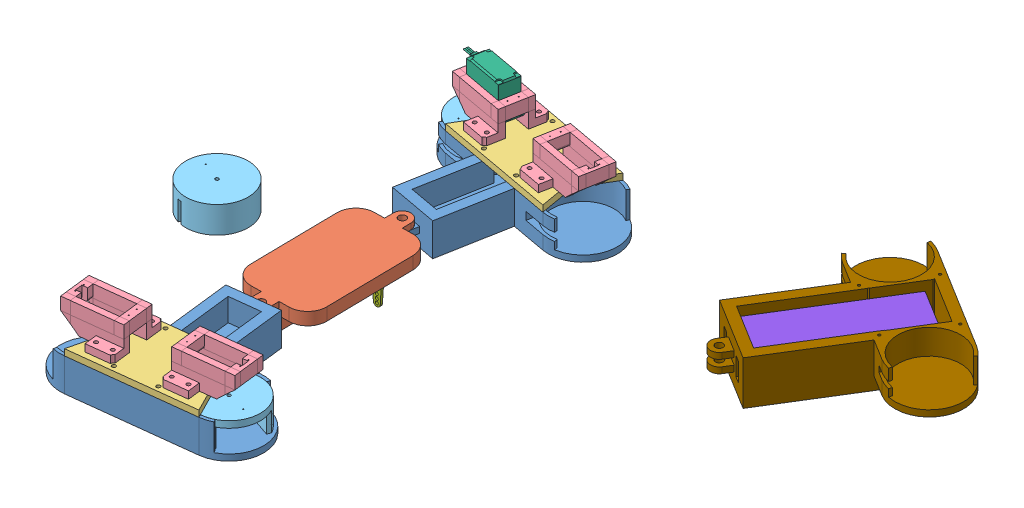
SolidWorks assembly X1 Spine Assem modified hips, configuration Default. Lengths in mm.
Overall size (536.46 176.29 640.27).
16 component instances, 9 part files, 32 mates.
Components (placement in the parent):
- hip joint v2-1: hip joint v2 [Default] at (-38.1106 25.7907 -1.081) x (0.983592 0 0.180406) z (-0.180406 0 0.983592) size (192.74 33.34 158.75)
- hip joint v2-2: hip joint v2 [Default] at (-44.6115 25.7907 344.185) x (-0.993229 0 0.116171) z (-0.116171 0 -0.993229) size (192.74 33.34 158.75)
- chassis base v1-1: chassis base v1 [Default] at (-56.3679 44.2057 170.9028) x (-0.014827 0 -0.99989) z (-0.99989 0 0.014827) size (162.56 25.4 76.2)
- servo mount plate hips V2-1: servo mount plate hips V2 [Default] at (-98.9089 52.7782 399.4918) x (0.993229 0 -0.116171) z (0.116171 0 0.993229) size (122.89 6.35 69.85)
- servo mount plate hips V2-2: servo mount plate hips V2 [Default] at (-103.4451 52.7782 8.5151) x (0.983592 0 0.180406) z (-0.180406 0 0.983592) size (122.89 6.35 69.85)
- servomount v1-1: servomount v1 [Default] at (-53.624 27.8862 359.0018) x (0.993229 0 -0.116171) z (0.116171 0 0.993229) size (57.78 27.96 58.16)
- servomount v1-2: servomount v1 [Default] at (-48.2722 27.8862 -16.9034) x (0.983592 0 0.180406) z (-0.180406 0 0.983592) size (57.78 27.96 58.16)
- servomount v1-3: servomount v1 [Default] at (-30.2613 27.8862 356.2692) x (-0.993229 0 0.116171) z (-0.116171 0 -0.993229) size (57.78 27.96 58.16)
- servomount v1-4: servomount v1 [Default] at (-25.1464 27.8862 -12.6038) x (-0.983592 0 -0.180406) z (0.180406 0 -0.983592) size (57.78 27.96 58.16)
- servo hip mount v2-1: servo hip mount v2 [Default] at (-97.1444 52.7782 -25.8368) x (0 -1 0) z (-0.811078 0 -0.584938) size (26.99 63.37 63.37)
- servo hip mount v2-2: servo hip mount v2 [Default] at (19.0878 52.7782 350.5274) x (0 -1 0) z (-0.323577 0 0.946202) size (26.99 63.37 63.37)
- servo hip mount v2-4: servo hip mount v2 [Default] at (-191.4073 38.335 152.321) x (0 -1 0) z (0.432407 0 -0.901679) size (26.99 63.37 63.37)
- sunfounder_20kgSLDPRT (1)-1: sunfounder_20kgSLDPRT (1) [Default] at (-85.0423 82.9862 -33.726) x (-0.180406 0 0.983592) z (0.983592 0 0.180406) size (20 46.03 62.2)
- 25T Servo Horn Steering Arm M3-1: 25T Servo Horn Steering Arm M3 [Default] at (-82.6215 -22.7927 99.0553) size (9.5 28 7.5)
- Battery-1: Battery [Default] at (172.4926 -38.8484 -113.9315) x (0.525988 0 -0.850492) z (0 -1 0) size (138.94 46.99 24.89)
- Battery hipshoulder joint-1: Battery hipshoulder joint [Default] at (196.1673 -54.8504 -144.1069) x (0.850492 0 0.525988) z (-0.525988 0 0.850492) size (192.74 44.45 184.15)
Mates (geometry in assembly coordinates):
- Coincident1: coincident anti-aligned: plane of hip joint v2-1 through (-43.8488 38.2367 91.7524) normal (0 1 0); plane of chassis base v1-1 through (-95.4052 38.2367 107.9747) normal (0 -1 0)
- Concentric1: concentric anti-aligned: cylinder of hip joint v2-1 through (-57.4446 7.7567 98.2971) axis (0 1 0) radius 3.81; cylinder of chassis base v1-1 through (-57.4446 48.2697 98.2971) axis (0 -1 0) radius 3.81
- Coincident2: coincident anti-aligned: plane of hip joint v2-2 through (-66.368 38.2367 253.7547) normal (0 1 0); plane of chassis base v1-1 through (-93.5223 38.2367 234.9607) normal (0 -1 0)
- Concentric2: concentric anti-aligned: cylinder of hip joint v2-2 through (-55.2913 7.7567 243.5085) axis (0 1 0) radius 3.81; cylinder of chassis base v1-1 through (-55.2913 48.2697 243.5085) axis (0 -1 0) radius 3.81
- Coincident3: coincident anti-aligned: plane of hip joint v2-2 through (-44.6115 52.7782 344.185) normal (0 1 0); plane of servo mount plate hips V2-1 through (-98.9089 52.7782 399.4918) normal (0 -1 0)
- Concentric3: concentric aligned: cylinder of hip joint v2-2 through (-58.6544 -36.8838 389.6689) axis (0 1 0) radius 1.2446; circle of servo mount plate hips V2-1
- Concentric4: concentric anti-aligned: cylinder of hip joint v2-2 through (-25.2239 -36.8838 325.6618) axis (0 1 0) radius 1.2446; cylinder of servo mount plate hips V2-1 through (-25.2239 59.1282 325.6618) axis (0 -1 0) radius 1.905
- Coincident4: coincident anti-aligned: plane of hip joint v2-1 through (-38.1106 52.7782 -1.081) normal (0 1 0); plane of servo mount plate hips V2-2 through (-103.4451 52.7782 8.5151) normal (0 -1 0)
- Concentric5: concentric anti-aligned: cylinder of hip joint v2-1 through (-11.3387 -36.8838 -40.4416) axis (0 1 0) radius 1.2446; cylinder of servo mount plate hips V2-2 through (-11.3387 59.1282 -40.4416) axis (0 -1 0) radius 1.905
- Concentric6: concentric anti-aligned: cylinder of hip joint v2-1 through (-62.0804 -36.8838 10.9373) axis (0 1 0) radius 1.2446; cylinder of servo mount plate hips V2-2 through (-62.0804 59.1282 10.9373) axis (0 -1 0) radius 1.905
- Concentric12: concentric aligned: cylinder of servo mount plate hips V2-1 through (-12.5318 52.7782 377.0805) axis (0 1 0) radius 1.2446; cylinder of servomount v1-1 through (-12.5318 53.798 377.0805) axis (0 1 0) radius 1.8415
- Parallel4: parallel aligned: plane of hip joint v2-2 through (-38.9627 52.7782 392.4803) normal (0.116171 0 0.993229); plane of servomount v1-1 through (-50.2457 27.8862 387.8849) normal (0.116171 0 0.993229)
- Coincident6: coincident anti-aligned: plane of servo mount plate hips V2-1 through (-98.9089 59.1282 399.4918) normal (0 1 0); plane of servomount v1-1 through (-11.9885 59.1282 425.4544) normal (0 -1 0)
- Concentric15: concentric aligned: cylinder of servo mount plate hips V2-1 through (-66.0723 52.7782 383.3428) axis (0 1 0) radius 1.2446; cylinder of servomount v1-3 through (-66.0723 53.798 383.3428) axis (0 1 0) radius 1.8415
- Parallel5: parallel aligned: plane of hip joint v2-2 through (-38.9627 52.7782 392.4803) normal (0.116171 0 0.993229); plane of servomount v1-3 through (-26.883 27.8862 385.1523) normal (0.116171 0 0.993229)
- Coincident7: coincident anti-aligned: plane of servo mount plate hips V2-1 through (-98.9089 59.1282 399.4918) normal (0 1 0); plane of servomount v1-3 through (-71.8968 59.1282 289.8167) normal (0 -1 0)
- Concentric16: concentric aligned: cylinder of servo mount plate hips V2-2 through (-14.2943 52.7782 12.4379) axis (0 1 0) radius 1.2446; cylinder of servomount v1-2 through (-14.2943 53.798 12.4379) axis (0 1 0) radius 1.8415
- Parallel6: parallel aligned: plane of servo mount plate hips V2-2 through (-103.4451 59.1282 8.5151) normal (-0.180406 0 0.983592); plane of servomount v1-2 through (-53.5184 27.8862 11.6995) normal (-0.180406 0 0.983592)
- Coincident8: coincident anti-aligned: plane of servo mount plate hips V2-2 through (-103.4451 59.1282 8.5151) normal (0 1 0); plane of servomount v1-2 through (-27.9702 59.1282 58.8415) normal (0 -1 0)
- Concentric18: concentric aligned: cylinder of servo mount plate hips V2-2 through (-74.1142 52.7782 -44.6944) axis (0 1 0) radius 1.2446; cylinder of servomount v1-4 through (-74.1142 53.798 -44.6944) axis (0 1 0) radius 1.8415
- Parallel7: parallel aligned: plane of servo mount plate hips V2-2 through (-103.4451 59.1282 8.5151) normal (-0.180406 0 0.983592); plane of servomount v1-4 through (-30.3926 27.8862 15.9991) normal (-0.180406 0 0.983592)
- Coincident9: coincident anti-aligned: plane of servo mount plate hips V2-2 through (-103.4451 59.1282 8.5151) normal (0 1 0); plane of servomount v1-4 through (-45.4484 59.1282 -88.3487) normal (0 -1 0)
- Coincident10: coincident anti-aligned: plane of hip joint v2-1 through (-38.1106 25.7907 -1.081) normal (0 1 0); plane of servo hip mount v2-1 through (-97.1444 25.7907 -25.8368) normal (0 -1 0)
- Concentric19: concentric anti-aligned: circle of hip joint v2-1; circle of servo hip mount v2-1
- Concentric20: concentric anti-aligned: circle of hip joint v2-2; circle of servo hip mount v2-2
- Coincident12: coincident anti-aligned: plane of hip joint v2-2 through (-44.6115 25.7907 344.185) normal (0 1 0); plane of servo hip mount v2-2 through (19.0878 25.7907 350.5274) normal (0 -1 0)
- Coincident13: coincident anti-aligned: plane of servomount v1-4 through (-116.8697 74.3862 -19.23) normal (0 -1 0); plane of sunfounder_20kgSLDPRT (1)-1 through (-58.4059 74.3862 -28.1796) normal (0 1 0)
- Coincident16: coincident anti-aligned: plane of servomount v1-4 through (-68.7819 -25.8348 -10.4099) normal (0.180406 0 -0.983592); plane of sunfounder_20kgSLDPRT (1)-1 through (-88.6504 82.9862 -14.0541) normal (-0.180406 0 0.983592)
- Coincident17: coincident anti-aligned: plane of servomount v1-4 through (-68.7819 -25.8348 -10.4099) normal (-0.983592 0 -0.180406); plane of sunfounder_20kgSLDPRT (1)-1 through (-68.7819 82.9862 -10.4099) normal (0.983592 0 0.180406)
- Coincident23: coincident anti-aligned: plane of Battery-1 through (172.4926 -63.7404 -113.9315) normal (0 -1 0); plane of Battery hipshoulder joint-1 through (150.1907 -63.7404 -188.6489) normal (0 1 0)
- Coincident24: coincident anti-aligned: plane of Battery-1 through (115.9704 -63.7404 -67.2068) normal (-0.850492 0 -0.525988); plane of Battery hipshoulder joint-1 through (110.6264 -54.8504 -58.5658) normal (0.850492 0 0.525988)
- Coincident25: coincident anti-aligned: plane of Battery-1 through (115.9704 -63.7404 -67.2068) normal (-0.525988 0 0.850492); plane of Battery hipshoulder joint-1 through (139.5786 -54.8504 -52.6063) normal (0.525988 0 -0.850492)
